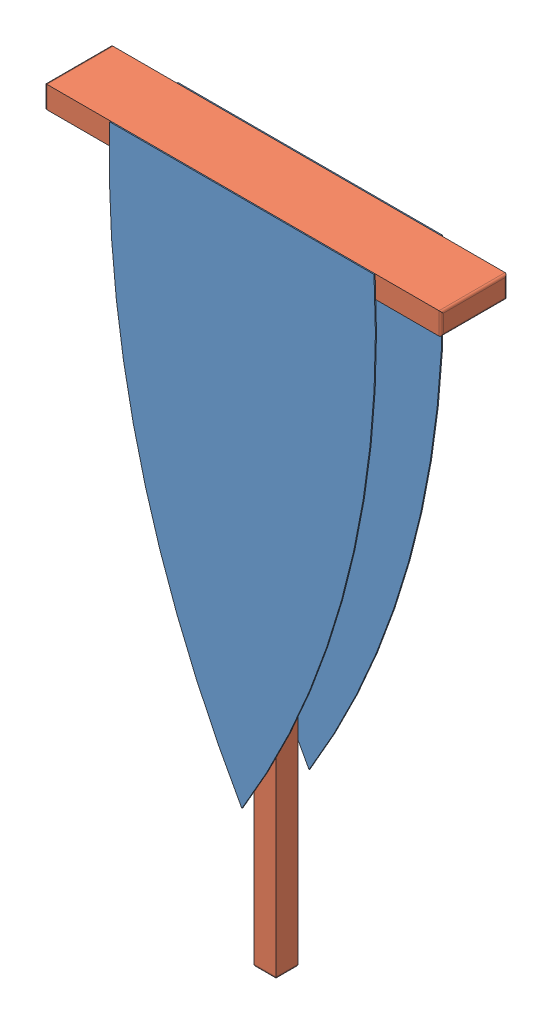
SolidWorks assembly bannercomp., configuration Default. Lengths in mm.
Overall size (457.2 787.4 78.74).
3 component instances, 2 part files, 6 mates.
Components (placement in the parent):
- banner-1: banner [Default] at (205.643 541.5527 327.6837) size (307 609.6 1.27)
- banner-2: banner [Default] at (205.643 541.5527 250.2137) size (307 609.6 1.27)
- bannerholder-1: bannerholder [Default] at (226.7156 541.5527 289.5837) x (1 0 0) z (0 -1 0) size (457.2 76.2 787.4)
Mates (geometry in assembly coordinates):
- Coincident1: coincident anti-aligned: plane of banner-1 through (-681.7007 482.9068 327.6837) normal (0 0 -1); plane of bannerholder-1 through (-1.8844 516.1527 327.6837) normal (0 0 1)
- Coincident2: coincident aligned: plane of banner-1 through (74.3156 541.5527 328.9537) normal (0 1 0); plane of bannerholder-1 through (226.7156 541.5527 289.5837) normal (0 1 0)
- Distance1: distance = 76.2 mm: plane of bannerholder-1 through (-1.8844 516.1527 251.4837) normal (-1 0 0); moEndPointRef_w of banner-1
- Coincident4: coincident anti-aligned: plane of banner-2 through (-681.7007 482.9068 251.4837) normal (0 0 1); plane of bannerholder-1 through (-1.8844 516.1527 251.4837) normal (0 0 -1)
- Coincident5: coincident aligned: plane of banner-2 through (74.3156 541.5527 251.4837) normal (0 1 0); plane of bannerholder-1 through (226.7156 541.5527 289.5837) normal (0 1 0)
- Distance2: distance = 76.2 mm: line of banner-2 through (379.1156 541.5527 251.4837) axis (0 0 -1); plane of bannerholder-1 through (455.3156 516.1527 251.4837) normal (1 0 0)
